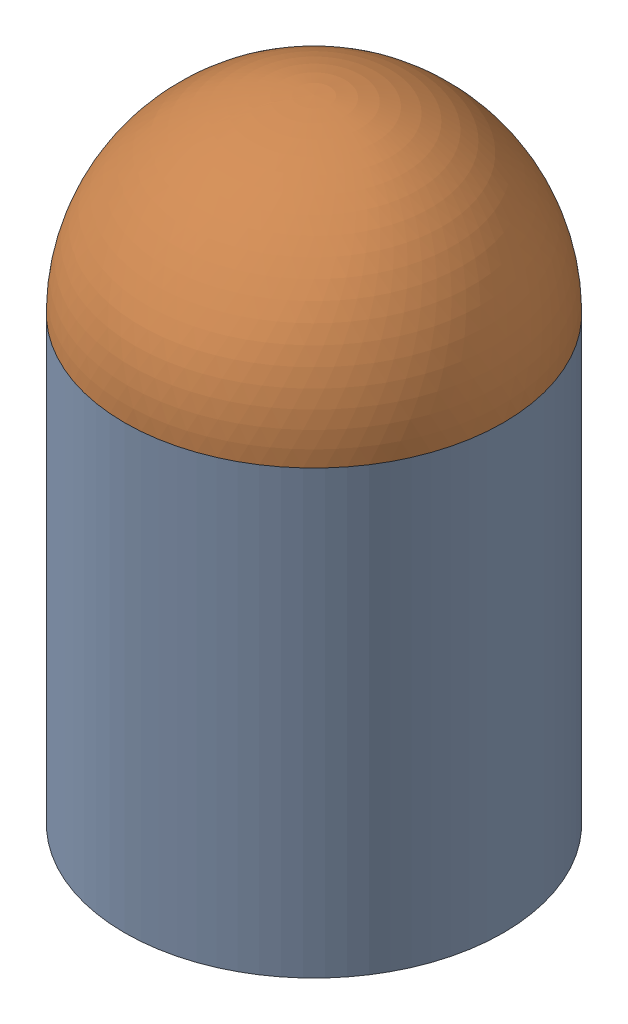
SolidWorks assembly monster_assem, configuration Default. Lengths in mm.
Overall size (105.47 127 105.47).
2 component instances, 2 part files, 2 mates.
Components (placement in the parent):
- monster_body-1: monster_body [Default] at (-8.9918 -40.7683 2.2435) size (76.2 88.9 76.2)
- monster_top-1: monster_top [Default] at (-8.9918 48.1317 2.2435) x (-0.837169 0 -0.546944) z (-0.546944 0 0.837169) size (76.2 38.1 76.2)
Mates (geometry in assembly coordinates):
- Coincident1: coincident: plane of monster_body-1 through (-8.9918 48.1317 2.2435) normal (0 1 0); plane of monster_top-1 through (-8.9918 48.1317 2.2435) normal (0 -1 0)
- Coincident2: coincident aligned: circle of monster_body-1; circle of monster_top-1
